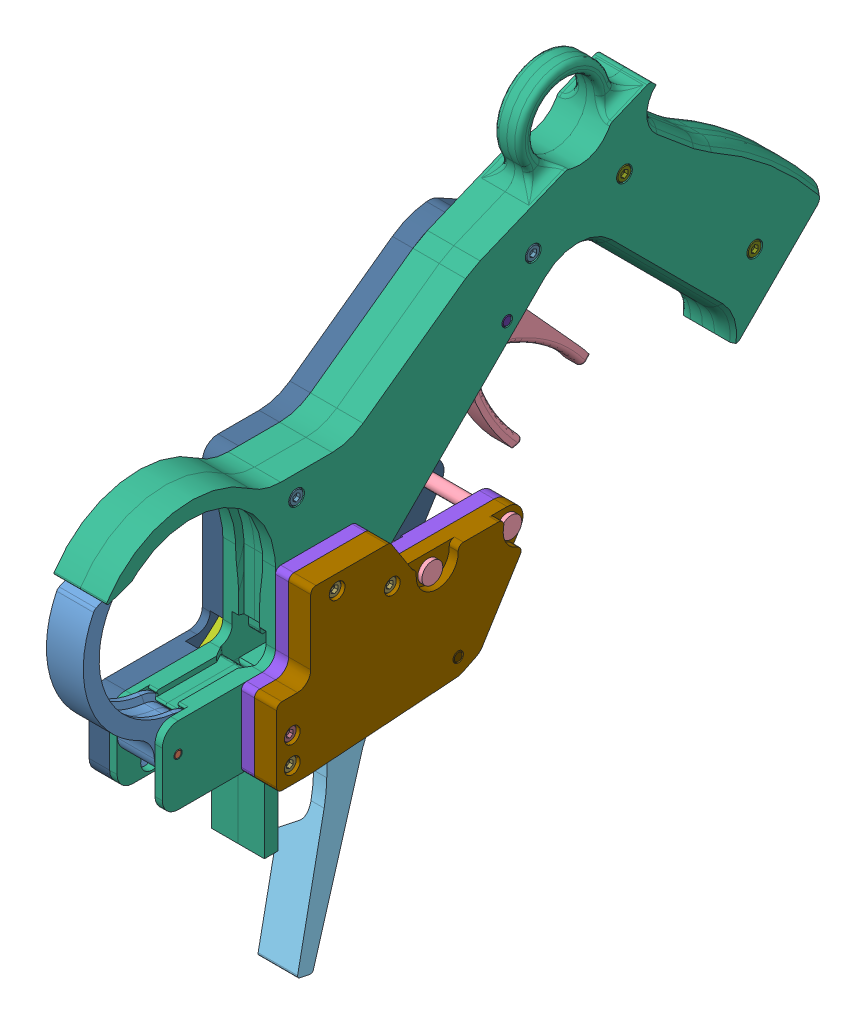
SolidWorks assembly Zip Tie Installer Main Part, configuration Default. Lengths in mm.
Overall size (41.53 235.41 278.93).
46 component instances, 25 part files, 0 mates.
Components (placement in the parent):
- Lower Jaw^Zip Tie Installer-1: Lower Jaw^Zip Tie Installer [Default] at origin size (14.21 80.48 47.55)
- Tightener Toothed Plate^Zip Tie Installer-1: Tightener Toothed Plate^Zip Tie Installer [Default] at origin size (3 10.24 9.42)
- Tightener Toothed Plate^Zip Tie Installer-2: Tightener Toothed Plate^Zip Tie Installer [Default] at (-3 0 0) size (3 10.24 9.42)
- Tightener Outer Arm^Zip Tie Installer-1: Tightener Outer Arm^Zip Tie Installer [Default] at origin size (12 37.58 22.8)
- Trigger^Zip Tie Installer-1: Trigger^Zip Tie Installer [Default] at origin size (8.25 68.11 69.93)
- Tightener Lever^Zip Tie Installer-1: Tightener Lever^Zip Tie Installer [Default] at origin size (15 108.92 63.63)
- Main Casing^Zip Tie Installer-1: Main Casing^Zip Tie Installer [Default] at origin size (20 198.72 273.04)
- Jaw Link^Zip Tie Installer-1: Jaw Link^Zip Tie Installer [Default] at origin size (10.4 114.15 109.74)
- Tightener Hinge Plate^Zip Tie Installer-1: Tightener Hinge Plate^Zip Tie Installer [Default] at origin size (5.57 60.99 96.96)
- Tightener Cover^Zip Tie Installer-1: Tightener Cover^Zip Tie Installer [Default] at origin size (8.4 60.99 96.96)
- Trigger Link Cover^Zip Tie Installer-1: Trigger Link Cover^Zip Tie Installer [Default] at origin size (7.8 125.13 144.29)
- socket head cap screw_am(B18.3.1M - 3 x 0.5 x 10 Hex SHCS -- 10NHX)-1: socket head cap screw_am(B18.3.1M - 3 x 0.5 x 10 Hex SHCS -- 10NHX) [Default] at (-6 -48.8276 -37) size (13 5.5 5.5)
- socket head cap screw_am(B18.3.1M - 3 x 0.5 x 10 Hex SHCS -- 10NHX)-2: socket head cap screw_am(B18.3.1M - 3 x 0.5 x 10 Hex SHCS -- 10NHX) [Default] at (-6 -43.5888 -39.925) size (13 5.5 5.5)
- socket head cap screw_am(B18.3.1M - 3 x 0.5 x 35 Hex SHCS -- 18NHX)-1: socket head cap screw_am(B18.3.1M - 3 x 0.5 x 35 Hex SHCS -- 18NHX) [Default] at (22.4 -55 -25) x (-1 0 0) z (0 0 -1) size (38 5.5 5.5)
- socket head cap screw_am(B18.3.1M - 3 x 0.5 x 35 Hex SHCS -- 18NHX)-2: socket head cap screw_am(B18.3.1M - 3 x 0.5 x 35 Hex SHCS -- 18NHX) [Default] at (22.4 -6 -42) x (-1 0 0) z (0 0 -1) size (38 5.5 5.5)
- socket head cap screw_am(B18.3.1M - 3 x 0.5 x 35 Hex SHCS -- 18NHX)-3: socket head cap screw_am(B18.3.1M - 3 x 0.5 x 35 Hex SHCS -- 18NHX) [Default] at (22.4 -15 -63) x (-1 0 0) z (0 0 -1) size (38 5.5 5.5)
- socket head cap screw_am(B18.3.1M - 3 x 0.5 x 25 Hex SHCS -- 18NHX)-1: socket head cap screw_am(B18.3.1M - 3 x 0.5 x 25 Hex SHCS -- 18NHX) [Default] at (22.4 -45 -25) x (-1 0 0) z (0 0 -1) size (28 5.5 5.5)
- socket head cap screw_am(B18.3.1M - 3 x 0.5 x 20 Hex SHCS -- 20NHX)-1: socket head cap screw_am(B18.3.1M - 3 x 0.5 x 20 Hex SHCS -- 20NHX) [Default] at (10 54.3811 -129.8944) x (-1 0 0) z (0 0 -1) size (23 5.5 5.5)
- socket head cap screw_am(B18.3.1M - 3 x 0.5 x 20 Hex SHCS -- 20NHX)-2: socket head cap screw_am(B18.3.1M - 3 x 0.5 x 20 Hex SHCS -- 20NHX) [Default] at (10 19 -40) x (-1 0 0) z (0 0 1) size (23 5.5 5.5)
- socket head cap screw_am(B18.3.1M - 3 x 0.5 x 5 Hex SHCS -- 5NHX)-1: socket head cap screw_am(B18.3.1M - 3 x 0.5 x 5 Hex SHCS -- 5NHX) [Default] at (18.8 -18.048 -52.44) x (-1 0 0) z (0 0 -1) size (8 5.5 5.5)
- socket head cap screw_am(B18.3.1M - 3 x 0.5 x 5 Hex SHCS -- 5NHX)-2: socket head cap screw_am(B18.3.1M - 3 x 0.5 x 5 Hex SHCS -- 5NHX) [Default] at (-4 12.452 -90.7449) x (1 0 0) z (0 0 -1) size (8 5.5 5.5)
- socket head cap screw_am(B18.3.1M - 3 x 0.5 x 5 Hex SHCS -- 5NHX)-3: socket head cap screw_am(B18.3.1M - 3 x 0.5 x 5 Hex SHCS -- 5NHX) [Default] at (18 -30.7609 -85.0495) x (-1 0 0) z (0 0 -1) size (8 5.5 5.5)
- socket head cap screw_am(B18.3.1M - 3 x 0.5 x 5 Hex SHCS -- 5NHX)-4: socket head cap screw_am(B18.3.1M - 3 x 0.5 x 5 Hex SHCS -- 5NHX) [Default] at (-4.8 -4.2604 -70.8277) x (1 0 0) z (0 0 -1) size (8 5.5 5.5)
- socket head cap screw_am(B18.3.1M - 3 x 0.5 x 16 Hex SHCS -- 16NHX)-1: socket head cap screw_am(B18.3.1M - 3 x 0.5 x 16 Hex SHCS -- 16NHX) [Default] at (10 63.163 -164.5477) x (-1 0 0) z (0 0 1) size (19 5.5 5.5)
- socket head cap screw_am(B18.3.1M - 3 x 0.5 x 16 Hex SHCS -- 16NHX)-2: socket head cap screw_am(B18.3.1M - 3 x 0.5 x 16 Hex SHCS -- 16NHX) [Default] at (10 13.6655 -214.0452) x (-1 0 0) z (0 0 1) size (19 5.5 5.5)
- Dowel Pin 4mm(20mm)-1: Dowel Pin 4mm(20mm) [Default] at (0 37 -120) x (0 0 1) z (-1 0 0) size (4 4 20)
- Dowel Pin 4mm(14mm)-1: Dowel Pin 4mm(14mm) [Default] at (16.43 -50.7609 -88) x (0 0 1) z (-1 0 0) size (4 4 14)
- Dowel Pin 3mm(9mm)-1: Dowel Pin 3mm(9mm) [Default] at (15.5 -24.9328 -45.1875) x (0 0 1) z (-1 0 0) size (3 3 9)
- Dowel Pin 3mm(26mm)-1: Dowel Pin 3mm(26mm) [Default] at (-3 -43 5) x (0 0 1) z (-1 0 0) size (3 3 26)
- Dowel Pin 3mm(18mm)-1: Dowel Pin 3mm(18mm) [Default] at (-5.4 -54.2415 -4.9312) x (0 0 1) z (-1 0 0) size (3 3 18)
- Dowel Pin 3mm(18mm)-2: Dowel Pin 3mm(18mm) [Default] at (-5.4 51.9102 -106.6701) x (0 0 1) z (-1 0 0) size (3 3 18)
- 90156A208_Flat-Head Quick-Release Pins-1: 90156A208_Flat-Head Quick-Release Pins [Default] at (1.7438 -20 -110) size (39.69 7.94 7.94)
- 90156A208_Flat-Head Quick-Release Pins-2: 90156A208_Flat-Head Quick-Release Pins [Default] at (1.7438 -20 -80) size (39.69 7.94 7.94)
- Extension Spring(26mm)-1: Extension Spring(26mm) [Default] at (-1.4 -1.0465 -74.6579) x (0 -0.766044 -0.642788) z (1 0 0) size (5.85 31.8 5.8)
- Extension Spring(35mm)-1: Extension Spring(35mm) [Default] at (15.4 -19.8641 -57.0985) x (0 -0.931701 0.363226) z (1 0 0) size (6.8 40.8 6.8)
- 94180A331_HEAT-SET INSERTS FOR PLASTICS-1: 94180A331_HEAT-SET INSERTS FOR PLASTICS [Default] at (-10 -15 -63) x (0 -1 0) z (0 0 1) size (5.56 4.12 5.56)
- 94180A331_HEAT-SET INSERTS FOR PLASTICS-2: 94180A331_HEAT-SET INSERTS FOR PLASTICS [Default] at (-10 54.3811 -129.8944) x (0 -1 0) z (0 0 1) size (5.56 4.12 5.56)
- 94180A331_HEAT-SET INSERTS FOR PLASTICS-3: 94180A331_HEAT-SET INSERTS FOR PLASTICS [Default] at (0 -45 -25) x (0 -1 0) z (0 0 1) size (5.56 4.12 5.56)
- 94180A331_HEAT-SET INSERTS FOR PLASTICS-4: 94180A331_HEAT-SET INSERTS FOR PLASTICS [Default] at (3 -48.8276 -37) x (0 1 0) z (0 0 1) size (5.56 4.12 5.56)
- 94180A331_HEAT-SET INSERTS FOR PLASTICS-5: 94180A331_HEAT-SET INSERTS FOR PLASTICS [Default] at (3 -43.5888 -39.925) x (0 1 0) z (0 0 1) size (5.56 4.12 5.56)
- 94180A331_HEAT-SET INSERTS FOR PLASTICS-6: 94180A331_HEAT-SET INSERTS FOR PLASTICS [Default] at (-10 -55 -25) x (0 -1 0) z (0 0 1) size (5.56 4.12 5.56)
- 94180A331_HEAT-SET INSERTS FOR PLASTICS-7: 94180A331_HEAT-SET INSERTS FOR PLASTICS [Default] at (-10 -43 5) x (0 -1 0) z (0 0 1) size (5.56 4.12 5.56)
- 94180A331_HEAT-SET INSERTS FOR PLASTICS-8: 94180A331_HEAT-SET INSERTS FOR PLASTICS [Default] at (0 13.6655 -214.0452) x (0 -1 0) z (0 0 1) size (5.56 4.12 5.56)
- 94180A331_HEAT-SET INSERTS FOR PLASTICS-9: 94180A331_HEAT-SET INSERTS FOR PLASTICS [Default] at (0 63.163 -164.5477) x (0 -1 0) z (0 0 1) size (5.56 4.12 5.56)
- 94180A331_HEAT-SET INSERTS FOR PLASTICS-10: 94180A331_HEAT-SET INSERTS FOR PLASTICS [Default] at (-10 -6 -42) x (0 -1 0) z (0 0 1) size (5.56 4.12 5.56)
- 94180A331_HEAT-SET INSERTS FOR PLASTICS-11: 94180A331_HEAT-SET INSERTS FOR PLASTICS [Default] at (-10 19 -40) x (0 -1 0) z (0 0 1) size (5.56 4.12 5.56)
